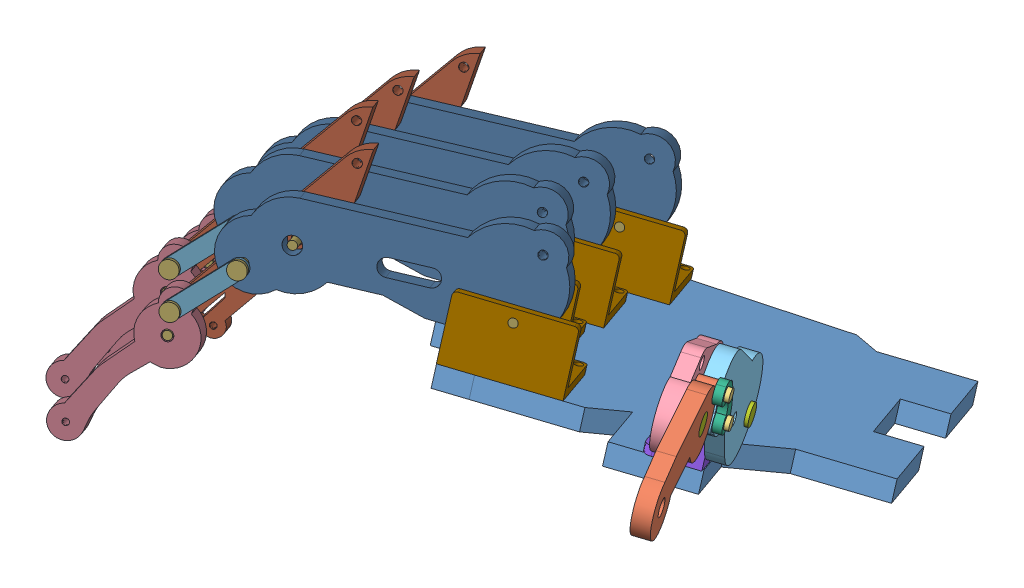
SolidWorks assembly Ensamble-Mano, configuration Default. Lengths in mm.
Overall size (192.77 110.94 154.58).
56 component instances, 14 part files, 15 mates.
Components (placement in the parent):
- palma 2-1: palma 2 [Predeterminado] at (73.49 47.7032 37.6797) x (0.476402 0.282755 0.832521) z (0.021316 -0.950313 0.310564) size (93.59 93.97 5)
- Assem2-1: Assem2 [Predeterminado] at (50.9838 94.4793 141.1129) x (-0.449773 0.09336 -0.88825) z (0.878969 -0.130208 -0.458759) size (79.33 53.45 19)
  - Part1-1: Part1 [Predeterminado] at (5.7204 6.7609 38.835) size (40.84 15 4)
  - Part10.4-1: Part10.4 [Predeterminado] at (12.8054 9.221 38.835) size (3 3 7)
  - Part2-1: Part2 [Predeterminado] at (22.7075 0.3342 34.835) x (0.949145 -0.31484 0) z (0 0 1) size (34.65 21.04 4)
  - Part3.1-1: Part3.1 [Predeterminado] at (37.251 -16.173 42.835) x (-0.661068 0.750326 0) z (0 0 -1) size (41.5 22 4)
  - Part5-1: Part5 [Predeterminado] at (12.8054 9.221 42.835) x (0.290265 -0.956946 0) z (0 0 1) size (15.17 7.17 2)
  - Part9.5-1: Part9.5 [Predeterminado] at (5.7204 6.7609 35.835) size (5 5 7)
  - Part9.5-2: Part9.5 [Predeterminado] at (22.7075 0.3342 34.835) size (5 5 7)
  - Part10.4-2: Part10.4 [Predeterminado] at (15.7564 -0.5078 38.835) size (3 3 7)
  - Part7.2-1: Part7.2 [Predeterminado] at (37.9356 -29.1185 32.835) x (-0.927361 0.374167 0) z (0.374167 0.927361 0) size (24 12 12)
  - Part9.5-4: Part9.5 [Predeterminado] at (41.3031 -20.7722 36.6646) size (5 5 7)
- Assem1-1: Assem1 [Default] at (-30.7507 21.7095 69.3524) x (0.879193 -0.144867 -0.453908) z (0.476402 0.282755 0.832521) size (98.82 77.15 18.06)
  - Base-union-1: Base-union [Default] at (40.7368 34.9498 5.6422) x (0.999881 0.015442 0) z (0.015442 -0.999881 0) size (25.11 17.06 15.06)
  - Dedo-inferior-1: Dedo-inferior [Default] at (-16.736 45.1395 -0.3578) x (0.997247 0.074154 0) z (0 0 1) size (68.17 25.78 4)
  - Dedo-medio-1: Dedo-medio [Default] at (-38.1998 17.0042 -4.3578) x (0.558156 0.829736 0) z (0 0 1) size (59.03 11.38 4)
  - Tornillo-0.10-1: Tornillo-0.10 [Default] at (-24.9374 38.9522 -0.3578) x (0.645348 0.763888 0) z (0 0 1) size (4 4 9)
  - Tornillo-0.10-2: Tornillo-0.10 [Default] at (-16.736 45.1395 3.6422) x (-0.566388 -0.824139 0) z (0 0 -1) size (4 4 9)
  - Tornillo-0.10-3: Tornillo-0.10 [Default] at (28.0815 44.9037 7.6422) x (-0.923728 -0.383049 0) z (0 0 -1) size (4 4 9)
  - Tornillo-0.10-4: Tornillo-0.10 [Default] at (-35.5482 26.9767 -0.3578) x (0.999969 -0.007893 0) z (0 0 1) size (4 4 9)
  - Tornillo-0.10-5: Tornillo-0.10 [Default] at (-35.7445 20.4797 3.6422) x (0.262 -0.965068 0) z (0 0 -1) size (4 4 9)
  - Dedo-punta-1: Dedo-punta [Default] at (-63.5967 -8.6033 -0.3578) x (0.538822 0.84242 0) z (0 0 1) size (39.74 13.26 4)
  - Union-2cm-1: Union-2cm [Default] at (-35.5482 26.9767 6.6422) x (0.663175 0.748465 0) z (0 0 1) size (20 4 1)
- Assem1-2: Assem1 [Default] at (-19.4959 34.882 108.8873) x (0.879193 -0.144867 -0.453908) z (0.476402 0.282755 0.832521) size (98.82 77.15 18.06)
  - Base-union-1: Base-union [Default] at (40.7368 34.9498 5.6422) x (0.999881 0.015442 0) z (0.015442 -0.999881 0) size (25.11 17.06 15.06)
  - Dedo-inferior-1: Dedo-inferior [Default] at (-16.736 45.1395 -0.3578) x (0.997247 0.074154 0) z (0 0 1) size (68.17 25.78 4)
  - Dedo-medio-1: Dedo-medio [Default] at (-38.1998 17.0042 -4.3578) x (0.558156 0.829736 0) z (0 0 1) size (59.03 11.38 4)
  - Tornillo-0.10-1: Tornillo-0.10 [Default] at (-24.9374 38.9522 -0.3578) x (0.645348 0.763888 0) z (0 0 1) size (4 4 9)
  - Tornillo-0.10-2: Tornillo-0.10 [Default] at (-16.736 45.1395 3.6422) x (-0.566388 -0.824139 0) z (0 0 -1) size (4 4 9)
  - Tornillo-0.10-3: Tornillo-0.10 [Default] at (28.0815 44.9037 7.6422) x (-0.923728 -0.383049 0) z (0 0 -1) size (4 4 9)
  - Tornillo-0.10-4: Tornillo-0.10 [Default] at (-35.5482 26.9767 -0.3578) x (0.999969 -0.007893 0) z (0 0 1) size (4 4 9)
  - Tornillo-0.10-5: Tornillo-0.10 [Default] at (-35.7445 20.4797 3.6422) x (0.262 -0.965068 0) z (0 0 -1) size (4 4 9)
  - Dedo-punta-1: Dedo-punta [Default] at (-63.5967 -8.6033 -0.3578) x (0.538822 0.84242 0) z (0 0 1) size (39.74 13.26 4)
  - Union-2cm-1: Union-2cm [Default] at (-35.5482 26.9767 6.6422) x (0.663175 0.748465 0) z (0 0 1) size (20 4 1)
- Assem1-3: Assem1 [Default] at (-27.2601 28.6123 90.2351) x (0.879193 -0.144867 -0.453908) z (0.476402 0.282755 0.832521) size (98.82 77.15 18.06)
  - Base-union-1: Base-union [Default] at (40.7368 34.9498 5.6422) x (0.999881 0.015442 0) z (0.015442 -0.999881 0) size (25.11 17.06 15.06)
  - Dedo-inferior-1: Dedo-inferior [Default] at (-16.736 45.1395 -0.3578) x (0.997247 0.074154 0) z (0 0 1) size (68.17 25.78 4)
  - Dedo-medio-1: Dedo-medio [Default] at (-38.1998 17.0042 -4.3578) x (0.558156 0.829736 0) z (0 0 1) size (59.03 11.38 4)
  - Tornillo-0.10-1: Tornillo-0.10 [Default] at (-24.9374 38.9522 -0.3578) x (0.645348 0.763888 0) z (0 0 1) size (4 4 9)
  - Tornillo-0.10-2: Tornillo-0.10 [Default] at (-16.736 45.1395 3.6422) x (-0.566388 -0.824139 0) z (0 0 -1) size (4 4 9)
  - Tornillo-0.10-3: Tornillo-0.10 [Default] at (28.0815 44.9037 7.6422) x (-0.923728 -0.383049 0) z (0 0 -1) size (4 4 9)
  - Tornillo-0.10-4: Tornillo-0.10 [Default] at (-35.5482 26.9767 -0.3578) x (0.999969 -0.007893 0) z (0 0 1) size (4 4 9)
  - Tornillo-0.10-5: Tornillo-0.10 [Default] at (-35.7445 20.4797 3.6422) x (0.262 -0.965068 0) z (0 0 -1) size (4 4 9)
  - Dedo-punta-1: Dedo-punta [Default] at (-63.5967 -8.6033 -0.3578) x (0.538822 0.84242 0) z (0 0 1) size (39.74 13.26 4)
  - Union-2cm-1: Union-2cm [Default] at (-35.5482 26.9767 6.6422) x (0.663175 0.748465 0) z (0 0 1) size (20 4 1)
- Assem1-4: Assem1 [Default] at (-4.4746 40.0767 123.7517) x (0.879193 -0.144867 -0.453908) z (0.476402 0.282755 0.832521) size (98.82 77.15 18.06)
  - Base-union-1: Base-union [Default] at (40.7368 34.9498 5.6422) x (0.999881 0.015442 0) z (0.015442 -0.999881 0) size (25.11 17.06 15.06)
  - Dedo-inferior-1: Dedo-inferior [Default] at (-16.736 45.1395 -0.3578) x (0.997247 0.074154 0) z (0 0 1) size (68.17 25.78 4)
  - Dedo-medio-1: Dedo-medio [Default] at (-38.1998 17.0042 -4.3578) x (0.558156 0.829736 0) z (0 0 1) size (59.03 11.38 4)
  - Tornillo-0.10-1: Tornillo-0.10 [Default] at (-24.9374 38.9522 -0.3578) x (0.645348 0.763888 0) z (0 0 1) size (4 4 9)
  - Tornillo-0.10-2: Tornillo-0.10 [Default] at (-16.736 45.1395 3.6422) x (-0.566388 -0.824139 0) z (0 0 -1) size (4 4 9)
  - Tornillo-0.10-3: Tornillo-0.10 [Default] at (28.0815 44.9037 7.6422) x (-0.923728 -0.383049 0) z (0 0 -1) size (4 4 9)
  - Tornillo-0.10-4: Tornillo-0.10 [Default] at (-35.5482 26.9767 -0.3578) x (0.999969 -0.007893 0) z (0 0 1) size (4 4 9)
  - Tornillo-0.10-5: Tornillo-0.10 [Default] at (-35.7445 20.4797 3.6422) x (0.262 -0.965068 0) z (0 0 -1) size (4 4 9)
  - Dedo-punta-1: Dedo-punta [Default] at (-63.5967 -8.6033 -0.3578) x (0.538822 0.84242 0) z (0 0 1) size (39.74 13.26 4)
  - Union-2cm-1: Union-2cm [Default] at (-35.5482 26.9767 6.6422) x (0.663175 0.748465 0) z (0 0 1) size (20 4 1)
Mates (geometry in assembly coordinates):
- Concentric1: concentric anti-aligned: circle of palma 2-1; circle of Assem2-1/Part7.2-1
- Parallel1: parallel aligned: line of palma 2-1 through (60.8729 62.5813 84.0721) axis (0.476402 0.282755 0.832521); line of Assem2-1/Part7.2-1 through (57.7245 60.829 78.9262) axis (0.476402 0.282755 0.832521)
- Coincident2: coincident anti-aligned: plane of palma 2-1 through (73.49 47.7032 37.6797) normal (-0.021316 0.950313 -0.310564); plane of Assem2-1/Part7.2-1 through (58.1675 65.0033 91.669) normal (0.021316 -0.950313 0.310564)
- Coincident5: coincident aligned: plane of palma 2-1 through (-20.1746 48.499 46.5435) normal (-0.878969 0.130208 0.458759); plane of Assem1-1/Base-union-1 through (-14.4493 51.897 56.5485) normal (-0.878969 0.130208 0.458759)
- Coincident6: coincident aligned: line of palma 2-1 through (-21.5656 47.6513 44.0452) axis (0.878969 -0.130208 -0.458759); line of Assem1-1/Base-union-1 through (-20.7164 47.5255 43.602) axis (0.878969 -0.130208 -0.458759)
- Coincident7: coincident anti-aligned: plane of palma 2-1 through (73.49 47.7032 37.6797) normal (-0.021316 0.950313 -0.310564); plane of Assem1-1/Base-union-1 through (7.5249 48.6419 45.0796) normal (0.021316 -0.950313 0.310564)
- Coincident9: coincident: plane of palma 2-1 through (-16.678 55.4053 67.4367) normal (-0.878969 0.130208 0.458759); plane of Assem1-3/Base-union-1 through (-11.1684 61.5747 76.2421) normal (-0.878969 0.130208 0.458759)
- Coincident10: coincident: line of palma 2-1 through (-18.1535 54.5657 64.9688) axis (0.878969 -0.130208 -0.458759); line of Assem1-3/Base-union-1 through (-17.2258 54.4283 64.4847) axis (0.878969 -0.130208 -0.458759)
- Coincident12: coincident anti-aligned: plane of palma 2-1 through (73.49 47.7032 37.6797) normal (-0.021316 0.950313 -0.310564); plane of Assem1-3/Base-union-1 through (11.0155 55.5447 65.9623) normal (0.021316 -0.950313 0.310564)
- Coincident13: coincident: plane of palma 2-1 through (-8.93 61.6655 86.0607) normal (-0.878969 0.130208 0.458759); plane of Assem1-2/Base-union-1 through (-3.1946 65.0696 96.0834) normal (-0.878969 0.130208 0.458759)
- Coincident14: coincident: plane of palma 2-1 through (73.49 47.7032 37.6797) normal (-0.021316 0.950313 -0.310564); plane of Assem1-2/Base-union-1 through (18.7796 61.8144 84.6145) normal (0.021316 -0.950313 0.310564)
- Coincident15: coincident aligned: line of palma 2-1 through (-10.3494 60.8295 83.6002) axis (0.878969 -0.130208 -0.458759); line of Assem1-2/Base-union-1 through (-9.4616 60.698 83.1369) axis (0.878969 -0.130208 -0.458759)
- Coincident16: coincident: plane of palma 2-1 through (73.49 47.7032 37.6797) normal (-0.021316 0.950313 -0.310564); plane of Assem1-4/Base-union-1 through (33.801 67.009 99.4789) normal (0.021316 -0.950313 0.310564)
- Coincident17: coincident: plane of palma 2-1 through (5.9354 66.7675 100.6525) normal (-0.878969 0.130208 0.458759); plane of Assem1-4/Base-union-1 through (11.8268 70.2642 110.9479) normal (-0.878969 0.130208 0.458759)
- Coincident18: coincident aligned: line of palma 2-1 through (4.7178 66.0174 98.4407) axis (0.878969 -0.130208 -0.458759); line of Assem1-4/Base-union-1 through (5.5597 65.8927 98.0013) axis (0.878969 -0.130208 -0.458759)
